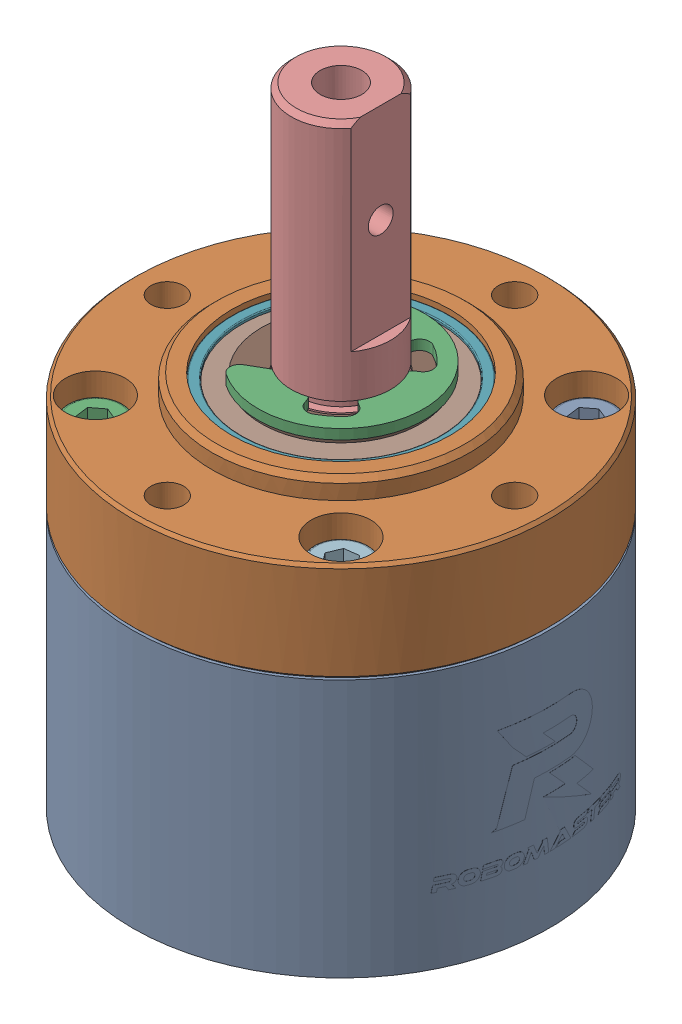
SolidWorks assembly 2, configuration ﾃﾞﾌｫﾙﾄ. Lengths in mm.
Overall size (59.4 63.3 59.4).
17 component instances, 8 part files, 0 mates.
Components (placement in the parent):
- 23-1: 23 [ﾃﾞﾌｫﾙﾄ] at origin size (42.01 26 42)
- 16-1: 16 [ﾃﾞﾌｫﾙﾄ] at (0 31 0) x (-0.707107 0 0.707107) z (0 1 0) size (42 42 14)
- 25-1: 25 [ﾃﾞﾌｫﾙﾄ] at (0 38.5 0) x (0 0 1) z (-1 0 0) size (16.7 1 13.43)
- 26-1: 26 [ﾃﾞﾌｫﾙﾄ] at (0 27 0) x (-0.381788 0 0.92425) z (-0.92425 0 -0.381788) size (22 6 22)
  - 27-1: 27 [ﾃﾞﾌｫﾙﾄ] at origin size (22 6 22)
  - 28-1: 28 [ﾃﾞﾌｫﾙﾄ] at (0 2.5 0) size (20 0.2 20)
  - 28-2: 28 [ﾃﾞﾌｫﾙﾄ] at (0 -2.7 0) size (20 0.2 20)
- 26-2: 26 [ﾃﾞﾌｫﾙﾄ] at (0 34.5 0) x (-0.381788 0 0.92425) z (-0.92425 0 -0.381788) size (22 6 22)
  - 27-1: 27 [ﾃﾞﾌｫﾙﾄ] at origin size (22 6 22)
  - 28-1: 28 [ﾃﾞﾌｫﾙﾄ] at (0 2.5 0) size (20 0.2 20)
  - 28-2: 28 [ﾃﾞﾌｫﾙﾄ] at (0 -2.7 0) size (20 0.2 20)
- 17-1: 17 [ﾃﾞﾌｫﾙﾄ] at (0 19.3 0) x (-1 0 0) z (0 0 -1) size (26 44 26)
- 24-1: 24 [ﾃﾞﾌｫﾙﾄ] at (0 37.71 0) x (0 1 0) z (0.381788 0 -0.92425) size (0.42 16 16)
- 18-1: 18 [ﾃﾞﾌｫﾙﾄ] at (12.3744 22 12.3744) x (-0.381788 0 0.92425) z (-0.92425 0 -0.381788) size (5.5 12 5.5)
- 18-2: 18 [ﾃﾞﾌｫﾙﾄ] at (12.3744 22 -12.3744) x (0.92425 0 0.381788) z (-0.381788 0 0.92425) size (5.5 12 5.5)
- 18-3: 18 [ﾃﾞﾌｫﾙﾄ] at (-12.3744 22 -12.3744) x (0.381788 0 -0.92425) z (0.92425 0 0.381788) size (5.5 12 5.5)
- 18-4: 18 [ﾃﾞﾌｫﾙﾄ] at (-12.3744 22 12.3744) x (-0.92425 0 -0.381788) z (0.381788 0 -0.92425) size (5.5 12 5.5)
